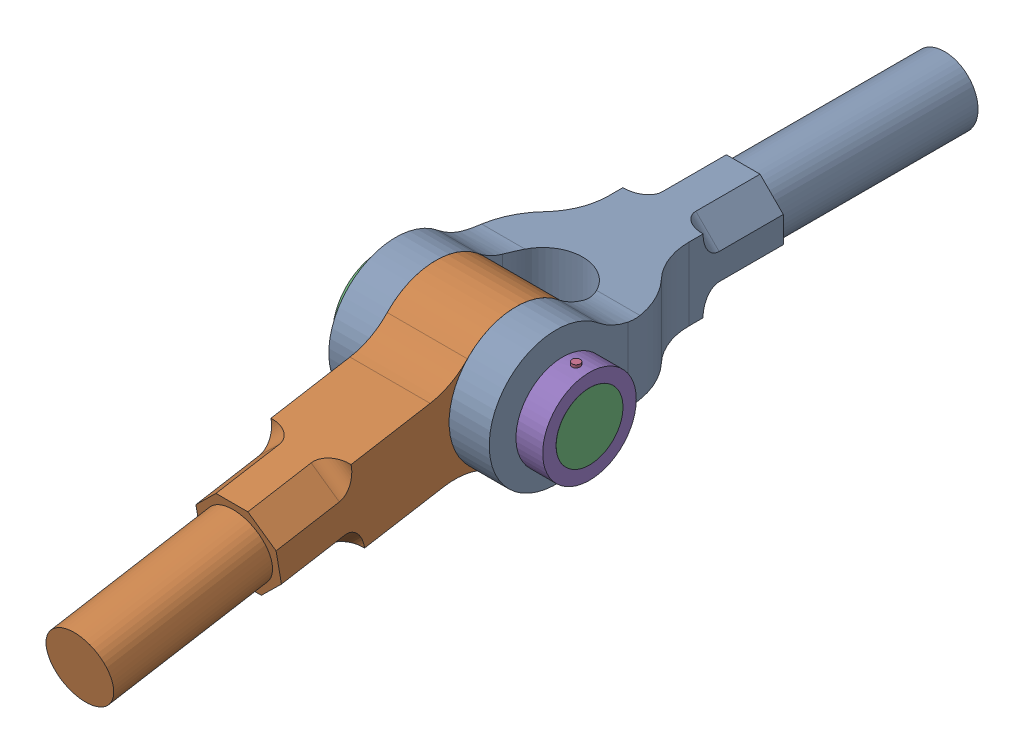
SolidWorks assembly knucklejoint, configuration Default. Lengths in mm.
Overall size (1577.7 1574.45 6553.29).
5 component instances, 5 part files, 8 mates.
Components (placement in the parent):
- forkpart-2: forkpart [Default] at (582.0081 -196.9615 257.1594) size (1200 1000 4007)
- eyepart-2: eyepart [Default] at (939.432 303.0385 960.2006) x (0 -0.167948 0.985796) z (-1 0 0) size (3505 1000 600)
- knucklepin-1: knucklepin [Default] at (341.9325 303.0385 881.5814) x (0.999985 0 -0.005515) z (0.005515 0 0.999985) size (1573.86 701.31 701.3)
- taperpin-1: taperpin [Default] at (1389.432 -46.9615 960.2006) size (60 720 60)
- collor-2: collor [Default] at (1289.432 303.0385 960.2006) x (0 0 -1) z (1 0 0) size (700 700 200)
Mates (geometry in assembly coordinates):
- Coincident2: coincident anti-aligned: circle of forkpart-2; circle of eyepart-2
- Concentric8: concentric anti-aligned: cylinder of eyepart-2 through (339.432 303.0385 960.2006) axis (1 0 0) radius 250; cone of knucklepin-1 through (1490.0092 303.0385 960.2006) axis (-1 0 0)
- Coincident3: coincident anti-aligned: plane of forkpart-2 through (39.432 803.0385 -1039.7994) normal (-1 0 0); plane of knucklepin-1 through (39.432 303.0385 718.2038) normal (1 0 0)
- Concentric12: concentric aligned: cone of knucklepin-1 through (1490.0092 303.0385 960.2006) axis (-1 0 0); cylinder of collor-2 through (1489.432 303.0385 960.2006) axis (-1 0 0) radius 250
- Concentric14: concentric aligned: cylinder of knucklepin-1 through (1389.432 -47.618 960.2006) axis (0 1 0) radius 30; cylinder of collor-2 through (1389.432 -46.9615 960.2006) axis (0 1 0) radius 30
- Concentric15: concentric anti-aligned: cylinder of taperpin-1 through (1389.432 673.0385 960.2006) axis (0 -1 0) radius 30; cylinder of collor-2 through (1389.432 -46.9615 960.2006) axis (0 1 0) radius 30
- Tangent7: tangent aligned: plane of taperpin-1 through (1389.432 -46.9615 960.2006) normal (0 -1 0); cylinder of collor-2 through (1489.432 303.0385 960.2006) axis (-1 0 0) radius 350
- LimitAngle5: limit planar angle = 3.310341 rad aligned: cylinder of eyepart-2 through (639.432 -201.6459 3922.517) axis (0 0.167948 -0.985796) radius 250; cylinder of forkpart-2 through (639.432 303.0385 -2546.7994) axis (0 0 1) radius 250
